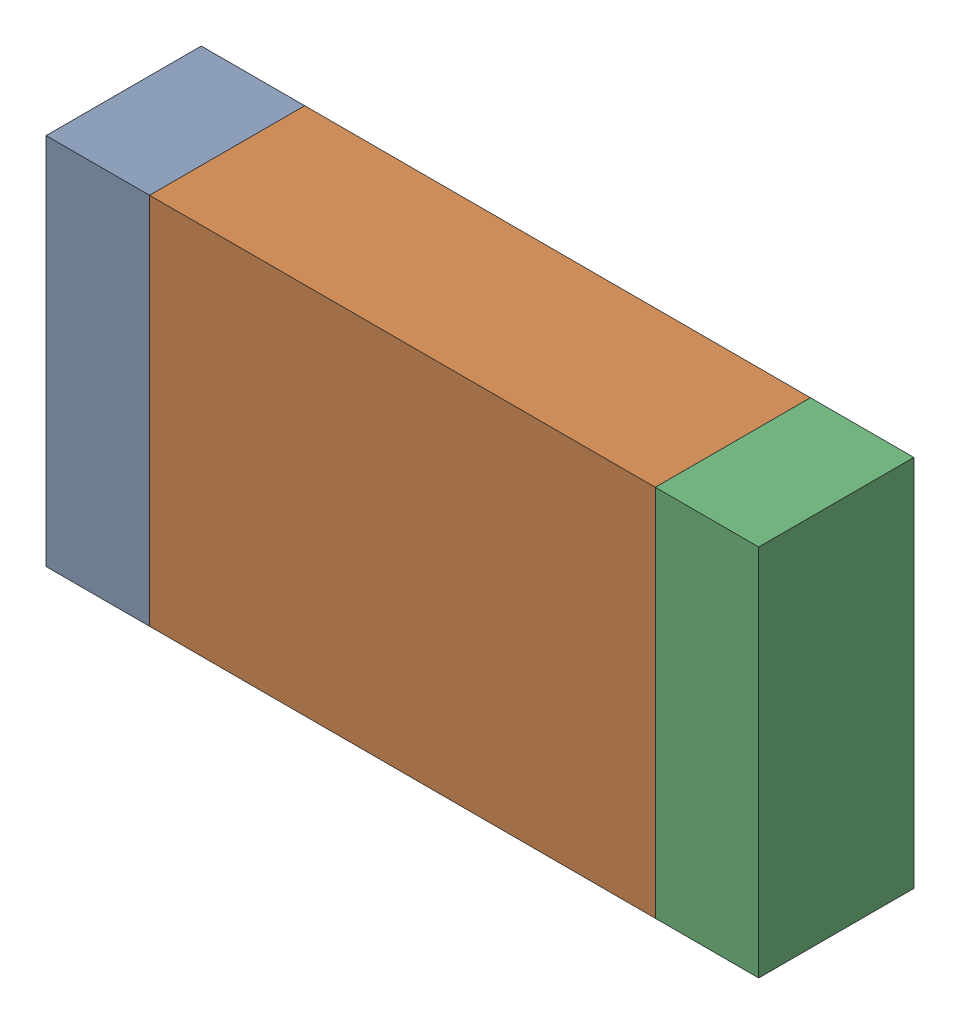
SolidWorks assembly C7, configuration Default. Lengths in mm.
Overall size (1.05 0.55 0.23).
6 component instances, 2 part files, 0 mates.
Components (placement in the parent):
- 822502864-1: 822502864 [Default] at (41.6053 11.1253 0.0254) size (0.15 0.55 0.23)
  - Extruded_8-1: Extruded_8 [Default] at origin size (0.15 0.55 0.23)
- 822503000-1: 822503000 [Default] at (42.0541 11.1253 0.0254) size (0.75 0.55 0.23)
  - Extruded_9-1: Extruded_9 [Default] at origin size (0.75 0.55 0.23)
- 822502864-2: 822502864 [Default] at (42.5029 11.1253 0.0254) size (0.15 0.55 0.23)
  - Extruded_8-1: Extruded_8 [Default] at origin size (0.15 0.55 0.23)
